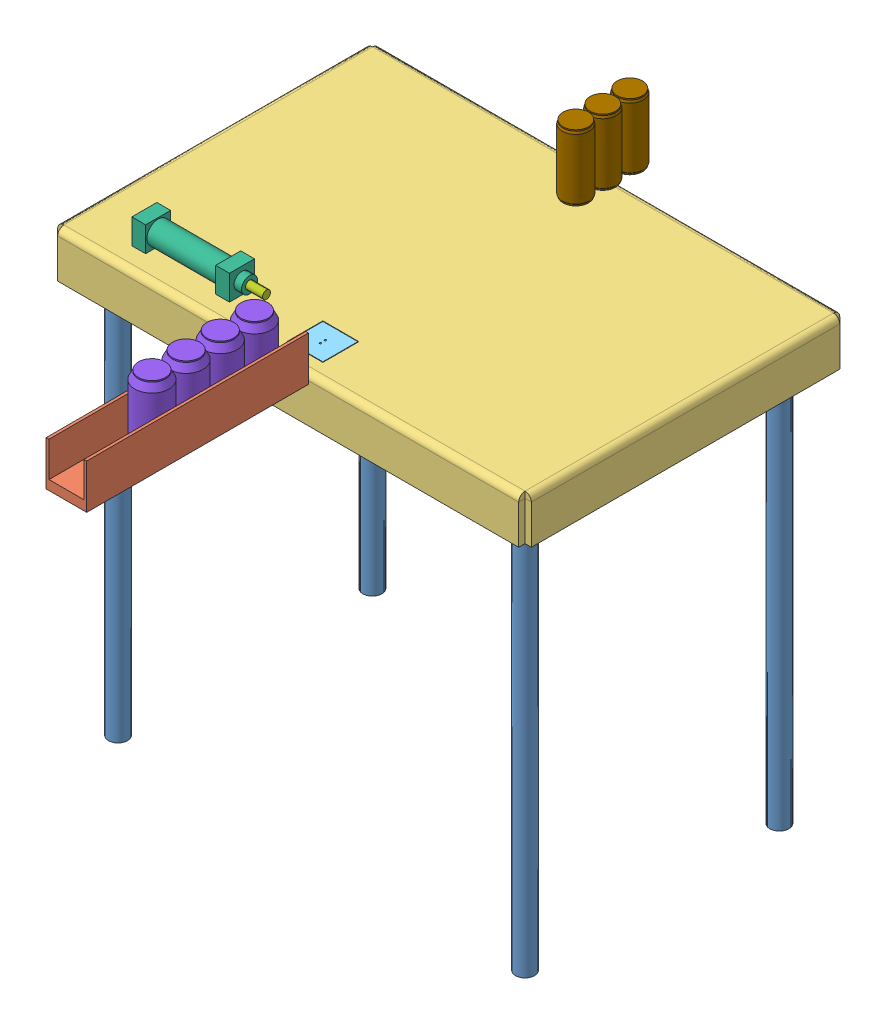
SolidWorks assembly Full_Assembly_v2, configuration Default. Lengths in mm.
Overall size (946.15 1065.21 1163.26).
15 component instances, 9 part files, 38 mates.
Components (placement in the parent):
- M37 Metal Table-1: M37 Metal Table [Default] at (-122.75 340.8931 1031.9817) size (914.4 863.6 609.6)
- Goose Output-1: Goose Output [Default] at (293.9688 417.0931 1047.8567) size (80.96 88.9 442.73)
- Table Topper-1: Table Topper [Default] at (-125.925 345.3431 1035.1567) size (946.15 90.8 641.35)
- Load Cell Assembly-1: Load Cell Assembly [Default] at (309.0555 378.227 899.7114) size (69.85 26.2 103.99)
  - Load Cell and Brace-1: Load Cell and Brace [Default] at (-9.1055 31.7162 92.7424) size (69 14.2 83)
  - scalePlate_v2_234-1: scalePlate_v2_234 [Default] at (-9.5305 57.9162 113.7283) x (0 0 -1) z (-1 0 0) size (69.85 12 69.85)
- Cylinder-1: Cylinder [Default] at (-22.0508 486.1431 953.5147) x (0 0 1) z (1 0 0) size (50 50 210)
- Rod-1: Rod [Default] at (221.9492 461.1431 978.5147) x (0 0.637822 -0.770184) z (0 0.770184 0.637822) size (16 134 16)
- can355mL-1: can355mL [Default] at (334.45 436.1431 1115.1412) x (0.989638 0 0.143588) z (-0.143588 0 0.989638) size (68.26 122.24 68.26)
- can355mL-2: can355mL [Default] at (334.45 436.1431 1251.6662) x (0.71438 0 -0.699758) z (0.699758 0 0.71438) size (68.26 122.24 68.26)
- can355mL-3: can355mL [Default] at (334.45 436.1431 1183.4037) x (-0.142529 0 -0.989791) z (0.989791 0 -0.142529) size (68.26 122.24 68.26)
- can250mL-1: can250mL [Default] at (334.45 436.1431 473.4181) x (0.051367 0 -0.99868) z (0.99868 0 0.051367) size (53.98 131.76 53.98)
- can250mL-2: can250mL [Default] at (334.45 436.1431 419.4431) x (0.934155 0 -0.356866) z (0.356866 0 0.934155) size (53.98 131.76 53.98)
- can250mL-3: can250mL [Default] at (334.45 436.1431 365.4681) x (0.679338 0 0.733825) z (-0.733825 0 0.679338) size (53.98 131.76 53.98)
- can355mL-7: can355mL [Default] at (334.45 436.1431 1319.9287) x (-0.751199 0 0.660076) z (-0.660076 0 -0.751199) size (68.26 122.24 68.26)
Mates (geometry in assembly coordinates):
- Width1: width aligned: plane of M37 Metal Table-1 through (791.65 366.2931 1031.9817) normal (1 0 0); plane of Table Topper-1 through (-122.75 366.2931 1031.9817) normal (-1 0 0); plane of M37 Metal Table-1 through (807.525 423.4431 1035.1567) normal (1 0 0); plane of Table Topper-1 through (-138.625 423.4431 1035.1567) normal (-1 0 0)
- Width2: width aligned: plane of M37 Metal Table-1 through (-122.75 366.2931 1031.9817) normal (0 0 1); plane of Table Topper-1 through (-122.75 366.2931 422.3817) normal (0 0 -1); plane of M37 Metal Table-1 through (-125.925 423.4431 1047.8567) normal (0 0 1); plane of Table Topper-1 through (-125.925 423.4431 406.5067) normal (0 0 -1)
- Distance1: distance = 863.6 mm aligned: plane of M37 Metal Table-1 through (-122.75 -446.5069 1031.9817) normal (0 -1 0); plane of Goose Output-1 through (374.9313 417.0931 1490.5914) normal (0 -1 0)
- LimitDistance1: limit distance = 432.5938 mm aligned: plane of Goose Output-1 through (374.9313 505.9931 1490.5914) normal (1 0 0); plane of Table Topper-1 through (807.525 423.4431 1035.1567) normal (1 0 0)
- LimitDistance2: limit distance = 432.5938 mm aligned: plane of Table Topper-1 through (-138.625 423.4431 1035.1567) normal (-1 0 0); plane of Goose Output-1 through (293.9688 417.0931 1490.5914) normal (-1 0 0)
- Parallel1: parallel aligned: plane of Goose Output-1 through (299.525 436.1431 1490.5914) normal (0 1 0); plane of Table Topper-1 through (-125.925 436.1431 1035.1567) normal (0 1 0)
- Coincident5: coincident aligned: plane of Goose Output-1 through (299.525 436.1431 1490.5914) normal (0 1 0); plane of Table Topper-1 through (-125.925 436.1431 1035.1567) normal (0 1 0)
- Coincident7: coincident aligned: plane of Table Topper-1 through (-125.925 436.1431 1035.1567) normal (0 1 0); plane of Load Cell Assembly-1/scalePlate_v2_234-1 through (299.525 436.1431 1013.4397) normal (0 1 0)
- Concentric1: concentric anti-aligned: cylinder of Cylinder-1 through (187.9492 461.1431 978.5147) axis (-1 0 0) radius 16; cylinder of Rod-1 through (87.9492 461.1431 978.5147) axis (1 0 0) radius 8
- LimitDistance3: limit distance = 34 mm aligned: plane of Rod-1 through (221.9492 461.1431 978.5147) normal (1 0 0); plane of Cylinder-1 through (187.9492 461.1431 978.5147) normal (1 0 0)
- Parallel2: parallel anti-aligned: plane of Table Topper-1 through (-125.925 423.4431 1047.8567) normal (0 0 1); plane of Cylinder-1 through (172.9492 486.1431 953.5147) normal (0 0 -1)
- Coincident9: coincident anti-aligned: plane of Table Topper-1 through (-125.925 436.1431 1035.1567) normal (0 1 0); plane of Cylinder-1 through (5.4492 436.1431 953.5147) normal (0 -1 0)
- Width3: width anti-aligned: plane of Goose Output-1 through (374.9313 505.9931 1490.5914) normal (1 0 0); plane of Load Cell Assembly-1/scalePlate_v2_234-1 through (293.9688 417.0931 1490.5914) normal (-1 0 0); plane of Goose Output-1 through (299.525 432.1431 1013.4397) normal (-1 0 0); plane of Load Cell Assembly-1/scalePlate_v2_234-1 through (369.375 432.1431 1013.4397) normal (1 0 0)
- Width4: width anti-aligned: plane of Cylinder-1 through (172.9492 486.1431 953.5147) normal (0 0 -1); plane of Load Cell Assembly-1/scalePlate_v2_234-1 through (172.9492 486.1431 1003.5147) normal (0 0 1); plane of Cylinder-1 through (299.525 432.1431 1013.4397) normal (0 0 1); plane of Load Cell Assembly-1/scalePlate_v2_234-1 through (299.525 432.1431 943.5897) normal (0 0 -1)
- Width5: width anti-aligned: plane of Table Topper-1 through (807.525 423.4431 1035.1567) normal (1 0 0); plane of Load Cell Assembly-1/scalePlate_v2_234-1 through (-138.625 423.4431 1035.1567) normal (-1 0 0); plane of Table Topper-1 through (299.525 432.1431 1013.4397) normal (-1 0 0); plane of Load Cell Assembly-1/scalePlate_v2_234-1 through (369.375 432.1431 1013.4397) normal (1 0 0)
- Coincident11: coincident anti-aligned: plane of Table Topper-1 through (-125.925 436.1431 1035.1567) normal (0 1 0); plane of can250mL-1 through (335.7548 436.1431 448.0516) normal (0 -1 0)
- Coincident18: coincident anti-aligned: plane of Table Topper-1 through (-125.925 436.1431 1035.1567) normal (0 1 0); plane of can355mL-2 through (353.7294 436.1431 1232.7815) normal (0 -1 0)
- Coincident19: coincident anti-aligned: plane of Table Topper-1 through (-125.925 436.1431 1035.1567) normal (0 1 0); plane of can355mL-3 through (330.6036 436.1431 1156.6917) normal (0 -1 0)
- Tangent5: tangent anti-aligned: cylinder of can355mL-2 through (334.45 436.1431 1251.6662) axis (0 -1 0) radius 34.1313; cylinder of can355mL-3 through (334.45 436.1431 1183.4037) axis (0 -1 0) radius 34.1313
- Width6: width: plane of Goose Output-1 through (299.525 505.9931 1490.5914) normal (1 0 0); plane of can250mL-1 through (369.375 436.1431 1490.5914) normal (-1 0 0); cylinder of Goose Output-1 through (334.45 436.1431 473.4181) axis (0 -1 0) radius 26.9875
- Width8: width: plane of Goose Output-1 through (369.375 436.1431 1490.5914) normal (-1 0 0); plane of can355mL-2 through (299.525 505.9931 1490.5914) normal (1 0 0); cylinder of Goose Output-1 through (334.45 436.1431 1251.6662) axis (0 -1 0) radius 34.1313
- Width10: width: plane of Goose Output-1 through (299.525 505.9931 1490.5914) normal (1 0 0); plane of can355mL-3 through (369.375 436.1431 1490.5914) normal (-1 0 0); cylinder of Goose Output-1 through (334.45 436.1431 1183.4037) axis (0 -1 0) radius 34.1313
- Coincident20: coincident anti-aligned: plane of Table Topper-1 through (-125.925 436.1431 1035.1567) normal (0 1 0); plane of can250mL-2 through (358.1776 436.1431 410.3787) normal (0 -1 0)
- Coincident21: coincident anti-aligned: plane of Table Topper-1 through (-125.925 436.1431 1035.1567) normal (0 1 0); plane of can250mL-3 through (351.7052 436.1431 384.1073) normal (0 -1 0)
- Tangent6: tangent anti-aligned: cylinder of can250mL-1 through (334.45 436.1431 473.4181) axis (0 -1 0) radius 26.9875; cylinder of can250mL-2 through (334.45 436.1431 419.4431) axis (0 -1 0) radius 26.9875
- Tangent7: tangent anti-aligned: cylinder of can250mL-2 through (334.45 436.1431 419.4431) axis (0 -1 0) radius 26.9875; cylinder of can250mL-3 through (334.45 436.1431 365.4681) axis (0 -1 0) radius 26.9875
- Width11: width: plane of Goose Output-1 through (299.525 505.9931 1490.5914) normal (1 0 0); plane of can250mL-2 through (369.375 436.1431 1490.5914) normal (-1 0 0); cylinder of Goose Output-1 through (334.45 436.1431 419.4431) axis (0 -1 0) radius 26.9875
- Width12: width: plane of Goose Output-1 through (299.525 505.9931 1490.5914) normal (1 0 0); plane of can250mL-3 through (369.375 436.1431 1490.5914) normal (-1 0 0); cylinder of Goose Output-1 through (334.45 436.1431 365.4681) axis (0 -1 0) radius 26.9875
- Coincident22: coincident anti-aligned: plane of Goose Output-1 through (293.9688 417.0931 1047.8567) normal (0 0 -1); plane of Table Topper-1 through (-125.925 423.4431 1047.8567) normal (0 0 1)
- Width14: width aligned: plane of Table Topper-1 through (370.391 345.3431 1014.4557) normal (-1 0 0); plane of Table Topper-1 through (298.509 345.3431 1014.4557) normal (1 0 0); plane of Load Cell Assembly-1/scalePlate_v2_234-1 through (299.525 432.1431 1013.4397) normal (-1 0 0); plane of Load Cell Assembly-1/scalePlate_v2_234-1 through (369.375 432.1431 1013.4397) normal (1 0 0)
- Width15: width anti-aligned: plane of Table Topper-1 through (298.509 345.3431 1014.4557) normal (0 0 -1); plane of Table Topper-1 through (298.509 345.3431 942.5737) normal (0 0 1); plane of Load Cell Assembly-1/scalePlate_v2_234-1 through (299.525 432.1431 1013.4397) normal (0 0 1); plane of Load Cell Assembly-1/scalePlate_v2_234-1 through (299.525 432.1431 943.5897) normal (0 0 -1)
- Width17: width: plane of Goose Output-1 through (369.375 436.1431 1490.5914) normal (-1 0 0); plane of Goose Output-1 through (299.525 505.9931 1490.5914) normal (1 0 0); cylinder of can355mL-4 through (334.45 436.1431 1259.8293) axis (0 -1 0) radius 34.1313
- Coincident31: coincident anti-aligned: plane of Table Topper-1 through (-125.925 436.1431 1035.1567) normal (0 1 0); plane of can355mL-7 through (314.1771 436.1431 1337.7425) normal (0 -1 0)
- Width19: width: plane of Goose Output-1 through (369.375 436.1431 1490.5914) normal (-1 0 0); plane of Goose Output-1 through (299.525 505.9931 1490.5914) normal (1 0 0); cylinder of can355mL-7 through (334.45 436.1431 1319.9287) axis (0 -1 0) radius 34.1313
- Coincident33: coincident anti-aligned: plane of Table Topper-1 through (-125.925 436.1431 1035.1567) normal (0 1 0); plane of can355mL-1 through (361.1579 436.1431 1119.0163) normal (0 -1 0)
- Tangent13: tangent anti-aligned: cylinder of can355mL-1 through (334.45 436.1431 1115.1412) axis (0 -1 0) radius 34.1313; cylinder of can355mL-3 through (334.45 436.1431 1183.4037) axis (0 -1 0) radius 34.1313
- Width20: width: plane of Goose Output-1 through (299.525 505.9931 1490.5914) normal (1 0 0); plane of Goose Output-1 through (369.375 436.1431 1490.5914) normal (-1 0 0); cylinder of can355mL-1 through (334.45 436.1431 1115.1412) axis (0 -1 0) radius 34.1313
- LimitDistance13: limit distance = 68.2625 mm: cylinder of can355mL-3 through (334.45 436.1431 1183.4037) axis (0 -1 0) radius 34.1313; cylinder of can355mL-7 through (334.45 436.1431 1319.9287) axis (0 -1 0) radius 34.1313
